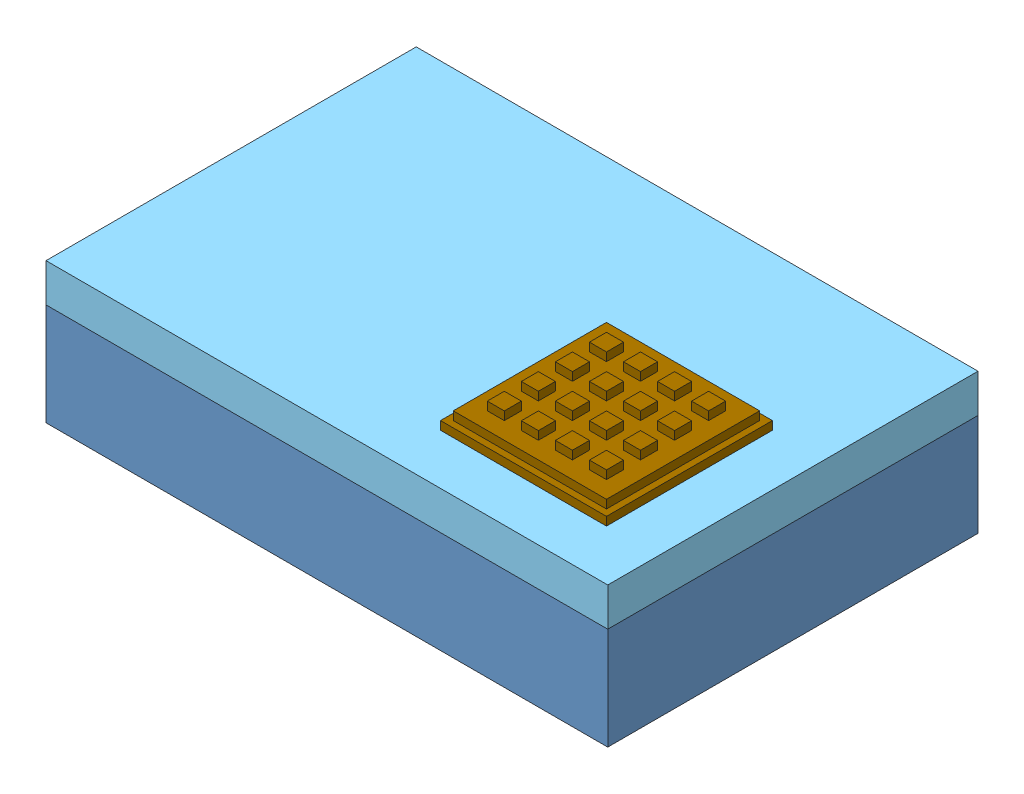
SolidWorks assembly PICase_Assembly_v5, configuration Default. Lengths in mm.
Overall size (220 64.9 145).
10 component instances, 9 part files, 31 mates.
Components (placement in the parent):
- PICase220x145x55_v1-1: PICase220x145x55_v1 [Default] at (-152.1826 -9.2207 87.4359) size (220 40 145)
- 12Vto5VMicroUsb_v1-1: 12Vto5VMicroUsb_v1 [Default] at (14.0667 11.0853 84.4359) x (1 0 0) z (0 1 0) size (63 14 42)
- RaspberryPi3B_v1-1: RaspberryPi3B_v1 [Default] at (-29.1826 -5.6074 11.5724) size (94 31 65.5)
- ProtoBoard_v1-1: ProtoBoard_v1 [Default] at (51.6118 3.5022 18.1693) x (-1 0 0) z (0 0 -1) size (80.96 1.59 50.8)
- ProtoBoard_v1-2: ProtoBoard_v1 [Default] at (-36.2767 9.5681 32.2155) x (0 0 -1) z (1 0 0) size (80.96 1.59 50.8)
- PICase_LID_220x145x55_v1-1: PICase_LID_220x145x55_v1 [Default] at (-152.1826 45.7793 -57.5641) x (1 0 0) z (0 0 -1) size (220 15 145)
- PowerSupply_v2-1: PowerSupply_v2 [Default] at (-149.1826 -6.2207 84.4359) size (138.11 32.54 53.98)
- 7seg_v1-1: 7seg_v1 [Default] at (-24.8229 33.2543 -20.3421) size (66 9.53 27)
- LCD_126x64_v1-1: LCD_126x64_v1 [Default] at (-132.818 32.4605 27.619) size (93.66 10.32 69.85)
- keyPad_4x4_v1-1: keyPad_4x4_v1 [Default] at (-17.3998 45.7793 67.7233) size (65 9.9 65)
Mates (geometry in assembly coordinates):
- Parallel1: parallel anti-aligned: plane of PICase220x145x55_v1-1 through (-152.1826 -6.2207 87.4359) normal (0 1 0); plane of RaspberryPi3B_v1-1 through (-29.1826 -5.6074 11.5724) normal (0 -1 0)
- Parallel2: parallel anti-aligned: plane of PICase220x145x55_v1-1 through (-152.1826 -6.2207 87.4359) normal (0 1 0); plane of ProtoBoard_v1-1 through (51.6118 3.5022 18.1693) normal (0 -1 0)
- Parallel4: parallel anti-aligned: plane of PICase220x145x55_v1-1 through (-152.1826 -9.2207 87.4359) normal (0 -1 0); plane of PICase_LID_220x145x55_v1-1 through (-152.1826 45.7793 -57.5641) normal (0 1 0)
- Coincident6: coincident aligned: plane of PICase220x145x55_v1-1 through (-152.1826 -6.2207 87.4359) normal (-1 0 0); plane of PICase_LID_220x145x55_v1-1 through (-152.1826 42.7793 -57.5641) normal (-1 0 0)
- Coincident9: coincident aligned: plane of PICase220x145x55_v1-1 through (-152.1826 -6.2207 87.4359) normal (0 0 1); plane of PICase_LID_220x145x55_v1-1 through (-152.1826 42.7793 87.4359) normal (0 0 1)
- LimitDistance1: limit distance = 0 mm anti-aligned: plane of PICase220x145x55_v1-1 through (-152.1826 30.7793 87.4359) normal (0 1 0); plane of PICase_LID_220x145x55_v1-1 through (-152.1826 30.7793 -57.5641) normal (0 -1 0)
- LimitDistance2: limit distance = 0.6133 mm anti-aligned: plane of RaspberryPi3B_v1-1 through (-29.1826 -5.6074 11.5724) normal (0 -1 0); plane of PICase220x145x55_v1-1 through (-152.1826 -6.2207 87.4359) normal (0 1 0)
- LimitDistance4: limit distance = 120 mm anti-aligned: plane of RaspberryPi3B_v1-1 through (-29.1826 25.3926 11.5724) normal (-1 0 0); plane of PICase220x145x55_v1-1 through (-149.1826 334.2655 -35.8641) normal (1 0 0)
- LimitDistance6: limit distance = 72.8635 mm anti-aligned: plane of PICase220x145x55_v1-1 through (-140.6826 334.2655 84.4359) normal (0 0 -1); plane of RaspberryPi3B_v1-1 through (-29.1826 25.3926 11.5724) normal (0 0 1)
- LimitDistance5: limit distance = 0.6133 mm anti-aligned: plane of RaspberryPi3B_v1-1 through (-29.1826 -5.6074 11.5724) normal (0 -1 0); plane of PICase220x145x55_v1-1 through (-152.1826 -6.2207 87.4359) normal (0 1 0)
- Parallel5: parallel anti-aligned: plane of PICase220x145x55_v1-1 through (-152.1826 -6.2207 87.4359) normal (0 1 0); plane of PowerSupply_v2-1 through (-149.1826 -6.2207 84.4359) normal (0 -1 0)
- Parallel6: parallel aligned: plane of PICase220x145x55_v1-1 through (-152.1826 -6.2207 87.4359) normal (0 0 1); plane of PowerSupply_v2-1 through (-149.1826 26.323 84.4359) normal (0 0 1)
- Parallel7: parallel aligned: plane of PICase220x145x55_v1-1 through (-152.1826 -6.2207 87.4359) normal (-1 0 0); plane of PowerSupply_v2-1 through (-149.1826 26.323 84.4359) normal (-1 0 0)
- LimitDistance7: limit distance = 0 mm anti-aligned: plane of PowerSupply_v2-1 through (-149.1826 26.323 84.4359) normal (-1 0 0); plane of PICase220x145x55_v1-1 through (-149.1826 334.2655 -35.8641) normal (1 0 0)
- LimitDistance8: limit distance = 0 mm anti-aligned: plane of PowerSupply_v2-1 through (-149.1826 26.323 84.4359) normal (0 0 1); plane of PICase220x145x55_v1-1 through (-140.6826 334.2655 84.4359) normal (0 0 -1)
- LimitDistance9: limit distance = 0 mm anti-aligned: plane of PowerSupply_v2-1 through (-149.1826 -6.2207 84.4359) normal (0 -1 0); plane of PICase220x145x55_v1-1 through (-152.1826 -6.2207 87.4359) normal (0 1 0)
- LimitDistance10: limit distance = 9.7229 mm anti-aligned: plane of ProtoBoard_v1-1 through (51.6118 3.5022 18.1693) normal (0 -1 0); plane of PICase220x145x55_v1-1 through (-152.1826 -6.2207 87.4359) normal (0 1 0)
- LimitDistance11: limit distance = 119.8319 mm anti-aligned: plane of PICase220x145x55_v1-1 through (-149.1826 334.2655 -35.8641) normal (1 0 0); plane of ProtoBoard_v1-1 through (-29.3507 5.0897 18.1693) normal (-1 0 0)
- LimitDistance12: limit distance = 15.4666 mm anti-aligned: plane of PICase220x145x55_v1-1 through (-140.6826 334.2655 84.4359) normal (0 0 -1); plane of ProtoBoard_v1-1 through (51.6118 5.0897 68.9693) normal (0 0 1)
- LimitDistance13: limit distance = 52.2203 mm anti-aligned: plane of PICase220x145x55_v1-1 through (-140.6826 334.2655 84.4359) normal (0 0 -1); plane of ProtoBoard_v1-2 through (-36.2767 11.1556 32.2155) normal (0 0 1)
- LimitDistance14: limit distance = 15.7888 mm anti-aligned: plane of PICase220x145x55_v1-1 through (-152.1826 -6.2207 87.4359) normal (0 1 0); plane of ProtoBoard_v1-2 through (-36.2767 9.5681 32.2155) normal (0 -1 0)
- LimitDistance15: limit distance = 62.1059 mm anti-aligned: plane of PICase220x145x55_v1-1 through (-149.1826 334.2655 -35.8641) normal (1 0 0); plane of ProtoBoard_v1-2 through (-87.0767 11.1556 32.2155) normal (-1 0 0)
- Coincident11: coincident anti-aligned: plane of PICase220x145x55_v1-1 through (-140.6826 334.2655 84.4359) normal (0 0 -1); plane of 12Vto5VMicroUsb_v1-1 through (14.0667 11.0853 84.4359) normal (0 0 1)
- Parallel8: parallel aligned: plane of PICase220x145x55_v1-1 through (-152.1826 -9.2207 87.4359) normal (0 -1 0); plane of 12Vto5VMicroUsb_v1-1 through (-8.9333 -4.9147 70.4359) normal (0 -1 0)
- LimitDistance16: limit distance = 1.306 mm anti-aligned: plane of PICase220x145x55_v1-1 through (-152.1826 -6.2207 87.4359) normal (0 1 0); plane of 12Vto5VMicroUsb_v1-1 through (-8.9333 -4.9147 70.4359) normal (0 -1 0)
- Coincident12: coincident anti-aligned: plane of PICase_LID_220x145x55_v1-1 through (-152.1826 42.7793 -57.5641) normal (0 -1 0); plane of 7seg_v1-1 through (-24.8229 42.7793 -20.3421) normal (0 1 0)
- Parallel9: parallel aligned: plane of PICase220x145x55_v1-1 through (-152.1826 -6.2207 -57.5641) normal (0 0 -1); plane of 7seg_v1-1 through (-19.1479 42.7793 -43.3671) normal (0 0 -1)
- Coincident14: coincident anti-aligned: plane of PICase_LID_220x145x55_v1-1 through (-152.1826 42.7793 -57.5641) normal (0 -1 0); plane of LCD_126x64_v1-1 through (-132.818 42.7793 27.619) normal (0 1 0)
- Parallel10: parallel aligned: plane of PICase220x145x55_v1-1 through (-152.1826 -6.2207 87.4359) normal (0 0 1); plane of LCD_126x64_v1-1 through (-132.818 34.048 27.619) normal (0 0 1)
- Coincident15: coincident anti-aligned: plane of PICase_LID_220x145x55_v1-1 through (-152.1826 45.7793 -57.5641) normal (0 1 0); plane of keyPad_4x4_v1-1 through (-17.3998 45.7793 67.7233) normal (0 -1 0)
- Parallel11: parallel aligned: plane of PICase220x145x55_v1-1 through (-152.1826 -6.2207 87.4359) normal (0 0 1); plane of keyPad_4x4_v1-1 through (-17.3998 49.0793 67.7233) normal (0 0 1)
